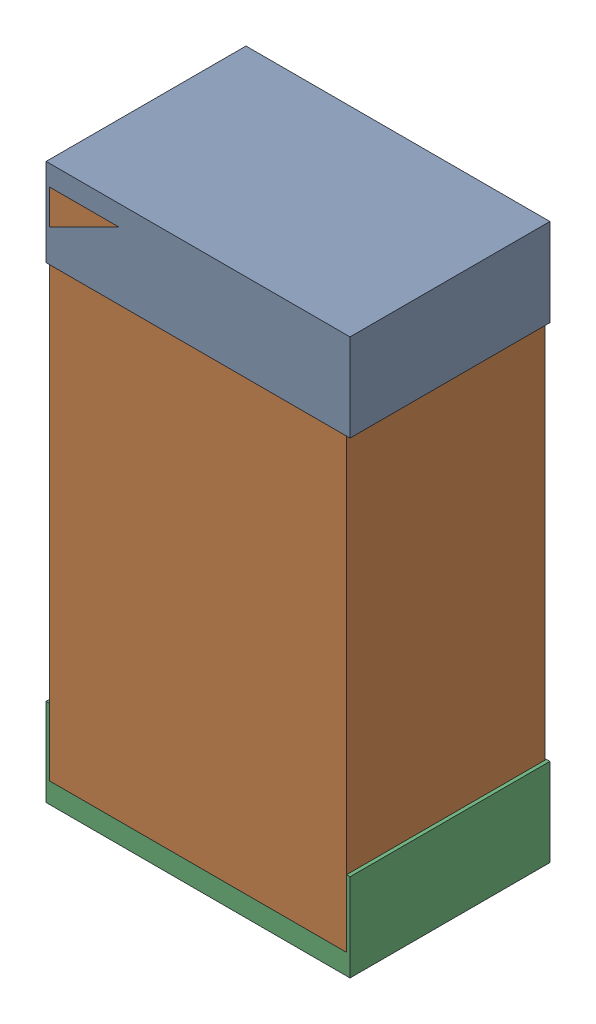
SolidWorks assembly R38Kanaloa_v2.0.0_Motor, configuration Default. Lengths in mm.
Overall size (1.3 2.38 0.85).
6 component instances, 2 part files, 0 mates.
Components (placement in the parent):
- 330415056-1: 330415056 [Default] at (94.234 122.92 -1.9574) size (1.3 0.38 0.85)
  - Extruded_2-1: Extruded_2 [Default] at origin size (1.3 0.38 0.85)
- 334787376-1: 334787376 [Default] at (94.234 121.92 -1.9524) size (1.27 2.2 0.85)
  - Extruded_16-1: Extruded_16 [Default] at origin size (1.27 2.2 0.85)
- 330415056-2: 330415056 [Default] at (94.234 120.92 -1.9574) size (1.3 0.38 0.85)
  - Extruded_2-1: Extruded_2 [Default] at origin size (1.3 0.38 0.85)
